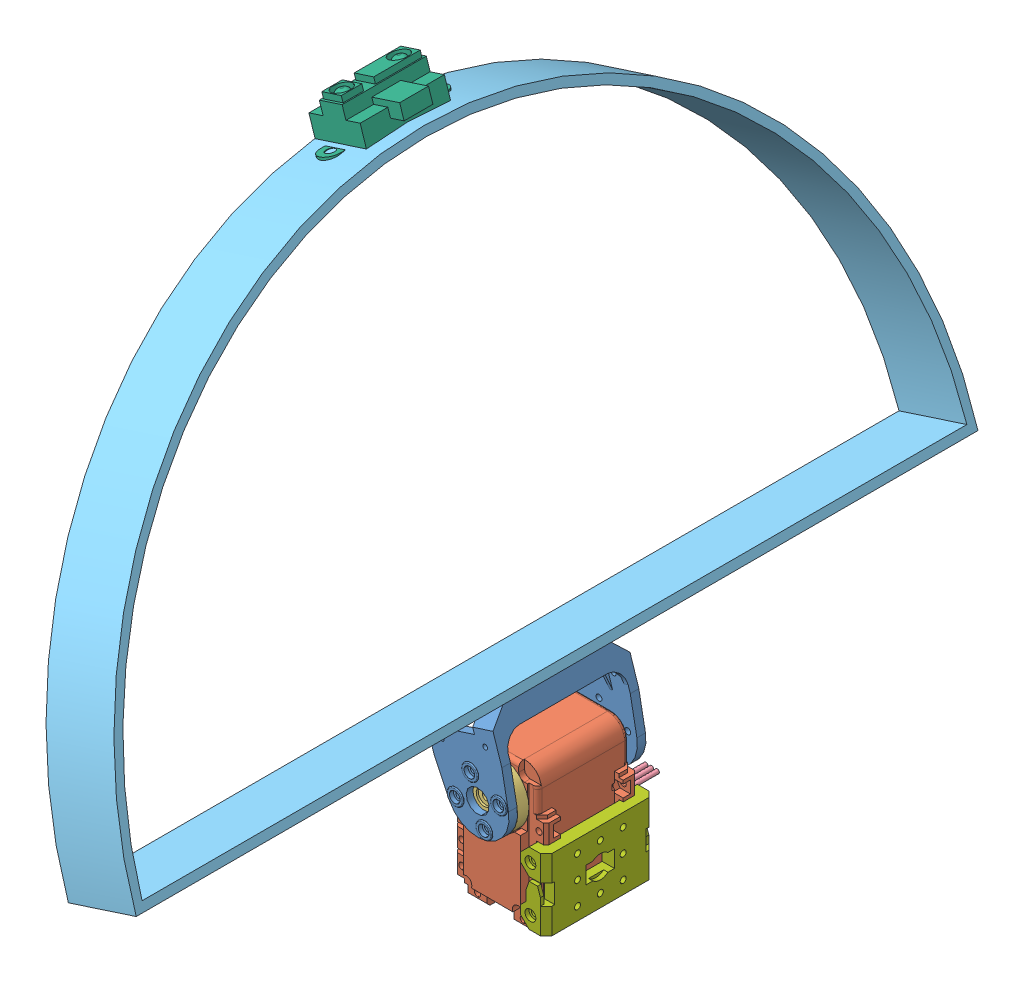
SolidWorks assembly Outil arceau commande centrale, configuration Défaut. Lengths in mm.
Overall size (89.33 221.87 295).
9 component instances, 7 part files, 12 mates.
Components (placement in the parent):
- F2-1: F2 [Défaut] at (138.6499 -30.9084 -243.8522) x (0 0 1) z (-0.309017 0.951057 0) size (48.81 25 37)
- servomoteur_ax-12-1: servomoteur_ax-12 [Default] at (141.3267 -52.7853 -239.5496) size (32 52.31 53.4)
  - AX-12_modif-1: AX-12_modif [Défaut] at (-2.6768 21.8769 -4.3025) size (32 50.06 38.01)
  - attache_ax-12-1: attache_ax-12 [Default] at (-2.6768 21.8769 12.6975) x (-0.301968 0.953318 0) z (0 0 1) size (22 22 4.7)
  - connecteur_AX-12-1: connecteur_AX-12 [Default] at (6.5732 8.6769 -17.5025) x (-1 0 0) z (0 -1 0) size (8 18.5 4)
  - connecteur_AX-12-2: connecteur_AX-12 [Default] at (-4.0768 8.6769 -17.5025) x (-1 0 0) z (0 -1 0) size (8 18.5 4)
- Arceau2-1: Arceau2 [Défaut] at (141.5766 0.535 -388.3522) x (0 0 1) z (-0.951057 -0.309017 0) size (295 150.5 25)
- GP2D12-1: GP2D12 [Default] at (91.1222 136.0776 -229.1022) x (0 0 -1) z (0.951057 0.309017 0) size (44.5 15.6 23.9)
- F3-1: F3 [Défaut] at (157.6538 -53.3585 -243.8522) x (0 1 0) z (0 0 1) size (25 9 38)
Mates (geometry in assembly coordinates):
- Coaxiale3: concentric aligned: cylinder of servomoteur_ax-12-1/attache_ax-12-1 through (138.6499 -30.9084 -226.8532) axis (0 0 1) radius 1.4; cylinder of F2-1 through (138.6499 -30.9084 -219.8522) axis (0 0 1) radius 4
- Coïncidente63: coincident anti-aligned: plane of servomoteur_ax-12-1/attache_ax-12-1 through (138.6499 -30.9084 -222.8522) normal (0 0 1); plane of F2-1 through (138.6499 -30.9084 -222.8522) normal (0 0 -1)
- Orientation arceau: planar angle = 0.314159 rad anti-aligned: plane of F2-1 through (147.1389 -16.5841 -267.8522) normal (0.951057 0.309017 0); plane of servomoteur_ax-12-1/AX-12_modif-1 through (125.6499 -24.6184 -258.9322) normal (-1 0 0)
- Coïncidente102: coincident anti-aligned: plane of servomoteur_ax-12-1/AX-12_modif-1 through (123.0499 -69.2884 -227.8522) normal (0 0 1); plane of F3-1 through (154.6538 -40.8585 -227.8522) normal (0 0 -1)
- Coïncidente69: coincident anti-aligned: plane of F2-1 through (142.5037 -2.3182 -267.8522) normal (-0.309017 0.951057 0); plane of Arceau2-1 through (118.7273 -10.0436 -243.8522) normal (0.309017 -0.951057 0)
- Tangent13: tangent: face of servomoteur_ax-12-1/AX-12_modif-1; cylinder of F3-1 through (152.1538 -45.3585 -224.8522) axis (0 0 1) radius 1.05
- Tangent14: tangent: face of servomoteur_ax-12-1/AX-12_modif-1; cylinder of F3-1 through (152.1538 -61.3585 -224.8522) axis (0 0 1) radius 1.05
- Coïncidente78: coincident: moEndPointRef_w of Arceau2-1; moEndPointRef_w of GP2D12-1
- Tangent6: tangent anti-aligned: cylinder of Arceau2-1 through (117.8002 -7.1905 -243.8522) axis (0.951057 0.309017 0) radius 144.5; plane of GP2D12-1 through (73.1473 130.2372 -229.1022) normal (0.309017 -0.951057 0)
- Pivot1: hinge anti-aligned: cylinder of servomoteur_ax-12-1/attache_ax-12-1 through (138.6499 -30.9084 -226.8532) axis (0 0 1) radius 1.4; cylinder of F2-1 through (138.6499 -30.9084 -219.8522) axis (0 0 1) radius 4; plane of servomoteur_ax-12-1/attache_ax-12-1 through (138.6499 -30.9084 -222.8522) normal (0 0 1); plane of F2-1 through (138.6499 -30.9084 -222.8522) normal (0 0 -1)
- Coïncidente103: coincident: unknown of F2-1; unknown of Arceau2-1
- PLAN1: unknown: plane of Arceau2-1 through (117.8002 -7.1905 -99.3522) normal (-0.309017 0.951057 0); unknown of Arceau2-1; plane of Arceau2-1 through (141.5766 0.535 -243.8522) normal (0.951057 0.309017 0)
